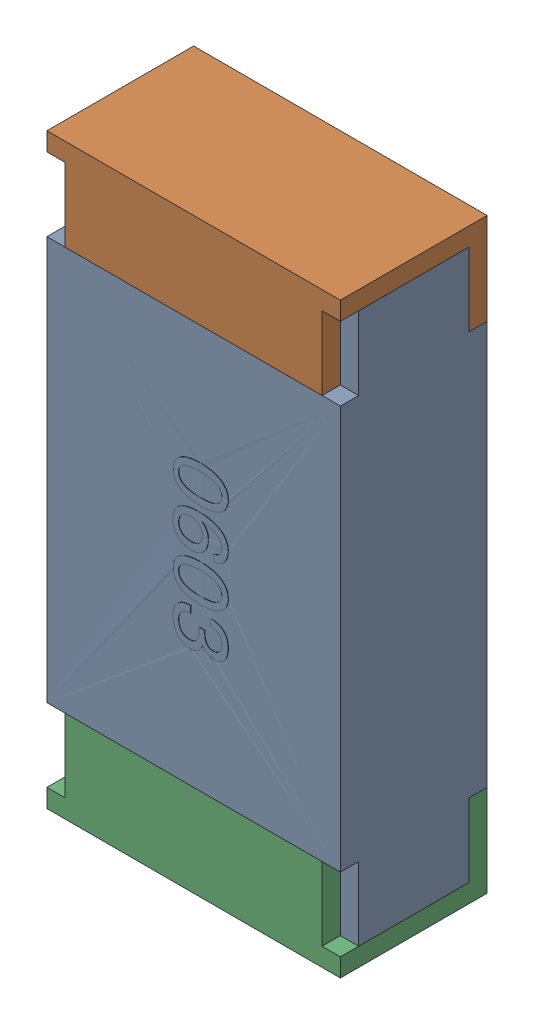
SolidWorks assembly R1, configuration 默认. Lengths in mm.
Overall size (0.8 1.6 0.41).
3 component instances, 2 part files, 0 mates.
Components (placement in the parent):
- R_0603-1: R_0603 [默认] at (75.184 72.136 0) x (0 -1 0) z (0 0 1) size (1.6 0.8 0.41)
  - R_0603-1: R_0603 [默认] at origin size (1.6 0.8 0.41)
  - LOGO__2-1: LOGO__2 [默认] at (0.0001 0.0322 -0.0016) x (-1 0 0) z (0 0 -1) size (0.48 0.55 0)
